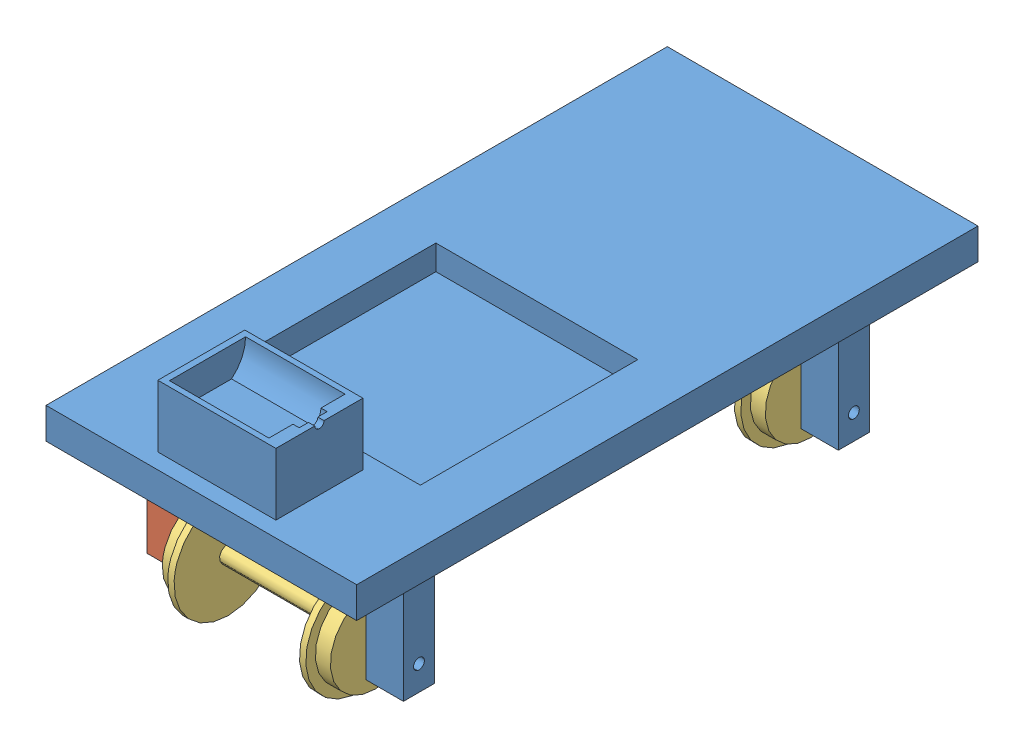
SolidWorks assembly Assem1, configuration Default. Lengths in mm.
Overall size (100.76 82.51 200).
6 component instances, 4 part files, 15 mates.
Components (placement in the parent):
- Body-1: Body [Default] at (88.2999 67.8 1070.4991) x (-1 0 0) z (0 0 -1) size (100 70 200)
- Rail-1: Rail [Default] at (87.0624 0 691.5866) x (1 0 0) z (0 1 0) size (70 1000 11.5) (hidden)
- Wheel leg-1: Wheel leg [Default] at (65.2499 57.8 1140.4991) x (-1 0 0) z (0 0 -1) size (28.46 48 39.5)
- Wheel leg-2: Wheel leg [Default] at (65.2499 57.8 1000.4991) x (-1 0 0) z (0 0 -1) size (28.46 48 39.5)
- Wheels-1: Wheels [Default] at (66.8824 25.8 1000.4991) x (0 0.193783 0.981045) z (-1 0 0) size (34.75 34.75 71.1)
- Wheels-2: Wheels [Default] at (66.8824 25.8 1140.4991) x (0 0.200513 0.979691) z (-1 0 0) size (34.75 34.75 71.1)
Mates (geometry in assembly coordinates):
- Coincident1: coincident anti-aligned: plane of Rail-1 through (87.0624 0 691.5866) normal (0 -1 0); plane of assembly through (0 0 0) normal (0 1 0)
- Coincident2: coincident: plane of Body-1 through (65.2499 67.8 1070.4991) normal (-1 0 0); plane of Wheel leg-2 through (65.2499 57.8 1000.4991) normal (1 0 0)
- Coincident3: coincident: plane of Body-1 through (65.2499 65.8 1020.4991) normal (0 -1 0); plane of Wheel leg-2 through (38.2999 65.8 980.7491) normal (0 1 0)
- Coincident6: coincident: plane of Body-1 through (65.2499 65.8 1120.4991) normal (0 -1 0); plane of Wheel leg-1 through (38.2999 65.8 1120.7491) normal (0 1 0)
- Coincident7: coincident: plane of Body-1 through (65.2499 67.8 1070.4991) normal (-1 0 0); plane of Wheel leg-1 through (65.2499 57.8 1140.4991) normal (1 0 0)
- Concentric1: concentric: cylinder of Wheel leg-1 through (37.544 25.8 1140.4991) axis (1 0 0) radius 1.75; cylinder of Wheels-2 through (122.6124 25.8 1140.4991) axis (-1 0 0) radius 1.485
- Width1: width: plane of Body-1 through (116.3499 17.8 1145.4991) normal (-1 0 0); plane of Wheel leg-1 through (57.7749 17.8 1135.4991) normal (1 0 0); plane of Wheels-2 through (107.2424 25.8 1140.4991) normal (-1 0 0); plane of Wheels-2 through (66.8824 25.8 1140.4991) normal (1 0 0)
- Width2: width: plane of Body-1 through (116.3499 17.8 995.4991) normal (-1 0 0); plane of Wheel leg-2 through (57.7749 17.8 995.4991) normal (1 0 0); plane of Wheels-1 through (66.8824 25.8 1000.4991) normal (1 0 0); plane of Wheels-1 through (107.2424 25.8 1000.4991) normal (-1 0 0)
- Concentric2: concentric: cylinder of Wheel leg-2 through (37.544 25.8 1000.4991) axis (1 0 0) radius 1.75; cylinder of Wheels-1 through (107.2424 25.8 1000.4991) axis (-1 0 0) radius 2.74
- Width3: width: plane of Body-1 through (65.2499 61.8 1020.4991) normal (0 0 -1); plane of Body-1 through (65.2499 65.8 980.4991) normal (0 0 1); plane of Wheel leg-2 through (38.2999 61.8 980.7491) normal (0 0 -1); plane of Wheel leg-2 through (38.2999 65.8 1020.2491) normal (0 0 1)
- Width4: width: plane of Body-1 through (65.2499 65.8 1160.4991) normal (0 0 -1); plane of Body-1 through (65.2499 61.8 1120.4991) normal (0 0 1); plane of Wheel leg-1 through (38.2999 61.8 1120.7491) normal (0 0 -1); plane of Wheel leg-1 through (38.2999 65.8 1160.2491) normal (0 0 1)
- Parallel1: parallel: plane of Body-1 through (88.2999 67.8 1070.4991) normal (0 1 0); plane of assembly through (0 0 0) normal (0 1 0)
- Parallel3: parallel: plane of Body-1 through (38.2999 57.8 970.4991) normal (0 0 -1); plane of assembly through (0 0 0) normal (0 0 1)
- Tangent2: tangent: plane of Rail-1 through (87.0624 11.5 691.5866) normal (0 1 0); cylinder of Wheels-1 through (114.1124 25.8 1000.4991) axis (-1 0 0) radius 14.3
- Width5: width: plane of Wheels-1 through (114.1124 25.8 1000.4991) normal (1 0 0); plane of Wheels-1 through (60.0124 25.8 1000.4991) normal (-1 0 0); plane of Rail-1 through (61.1574 11.5 1191.5866) normal (-1 0 0); plane of Rail-1 through (112.9674 11.5 191.5866) normal (1 0 0)
